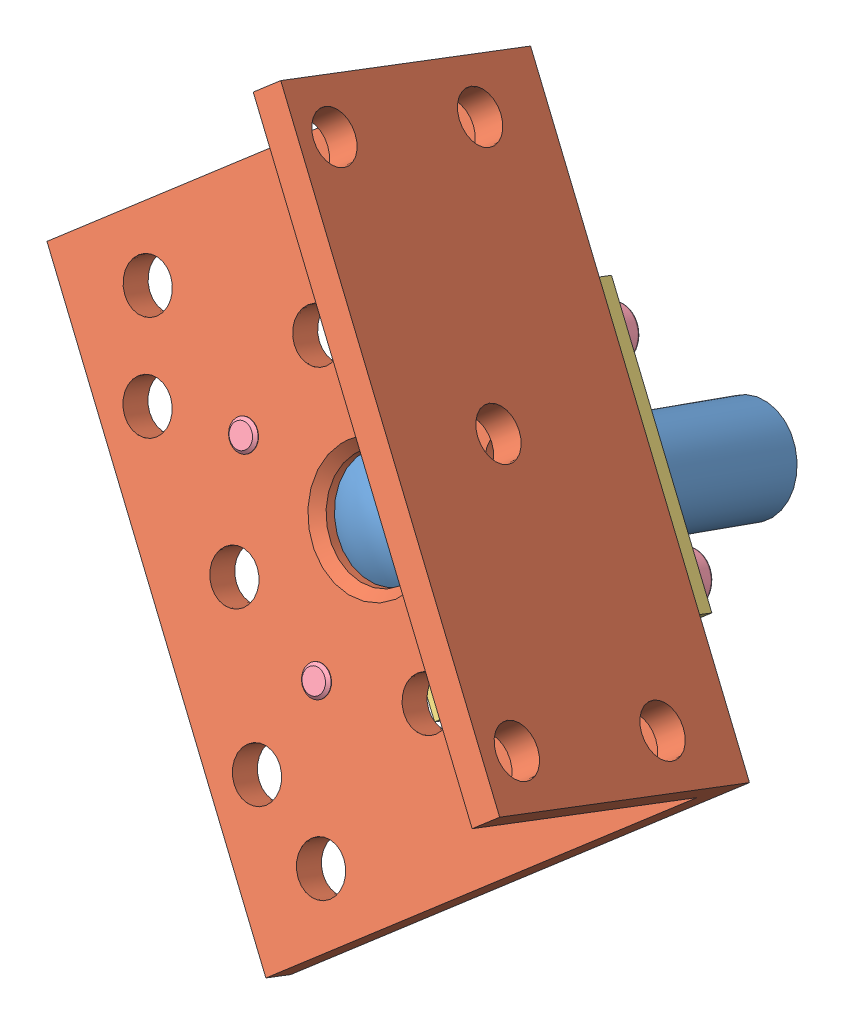
SolidWorks assembly Assemblage rotule v2, configuration Défaut. Lengths in mm.
Overall size (155.49 167.29 169.97).
7 component instances, 4 part files, 14 mates.
Components (placement in the parent):
- rotule v2-1: rotule v2 [Défaut] at (-163.3513 51.3692 -159.123) x (0.573473 -0.772184 0.273605) z (-0.81922 -0.539497 0.194477) size (38 87.57 38)
- support rotule v2-2: support rotule v2 [Défaut] at (-160.5548 83.4828 -76.8014) x (-0.661926 0.702138 -0.262403) z (-0.018758 -0.365479 -0.930631) size (120 100 60)
- plaque dessus rotule v2-2: plaque dessus rotule v2 [Défaut] at (-163.4271 69.4856 -107.0098) x (-0.661926 0.702138 -0.262403) z (-0.018758 -0.365479 -0.930631) size (55 55 6)
- m6x40-1: m6x40 [Défaut] at (-165.2878 41.0282 -102.2437) x (-0.14145 0.922402 -0.359396) z (-0.018758 -0.365479 -0.930631) size (10 10 46)
- m6x40-2: m6x40 [Défaut] at (-135.3145 65.4717 -112.4473) x (-0.230019 -0.90425 0.359755) z (-0.018758 -0.365479 -0.930631) size (10 10 46)
- m6x40-3: m6x40 [Défaut] at (-161.7915 93.5572 -122.9434) x (0.980648 -0.18815 0.054125) z (-0.018758 -0.365479 -0.930631) size (10 10 46)
- m6x40-4: m6x40 [Défaut] at (-191.7649 69.1137 -112.7398) x (0.7809 -0.586622 0.214639) z (-0.018758 -0.365479 -0.930631) size (10 10 46)
Mates (geometry in assembly coordinates):
- Parallèle4: parallel aligned: plane of support rotule v2-2 through (-237.8496 92.8639 -85.3748) normal (-0.749334 -0.611087 0.255091); plane of plaque dessus rotule v2-2 through (-202.3493 69.7966 -112.7946) normal (-0.749334 -0.611087 0.255091)
- Tangent1: tangent aligned: sphere of rotule v2-1; cone of support rotule v2-2 through (-162.8778 80.1877 -79.7586) axis (0.018758 0.365479 0.930631)
- Coaxiale4: concentric: sphere of rotule v2-1; cylinder of support rotule v2-2 through (-163.1029 75.8019 -90.9262) axis (0.018758 0.365479 0.930631) radius 11
- Parallèle5: parallel anti-aligned: plane of support rotule v2-2 through (-160.6674 81.29 -82.3852) normal (-0.018758 -0.365479 -0.930631); plane of plaque dessus rotule v2-2 through (-163.4271 69.4856 -107.0098) normal (0.018758 0.365479 0.930631)
- Coaxiale7: concentric: sphere of rotule v2-1; cylinder of plaque dessus rotule v2-2 through (-163.5397 67.2927 -112.5935) axis (0.018758 0.365479 0.930631) radius 11.5
- Coïncidente5: coincident anti-aligned: plane of plaque dessus rotule v2-2 through (-163.5397 67.2927 -112.5935) normal (-0.018758 -0.365479 -0.930631); plane of m6x40-1 through (-165.2878 41.0282 -102.2437) normal (0.018758 0.365479 0.930631)
- Coaxiale8: concentric anti-aligned: cylinder of plaque dessus rotule v2-2 through (-165.2878 41.0282 -102.2437) axis (0.018758 0.365479 0.930631) radius 3; cylinder of m6x40-1 through (-164.5375 55.6473 -65.0184) axis (-0.018758 -0.365479 -0.930631) radius 3
- Coïncidente6: coincident anti-aligned: plane of plaque dessus rotule v2-2 through (-163.5397 67.2927 -112.5935) normal (-0.018758 -0.365479 -0.930631); plane of m6x40-2 through (-135.3145 65.4717 -112.4473) normal (0.018758 0.365479 0.930631)
- Coaxiale9: concentric anti-aligned: cylinder of plaque dessus rotule v2-2 through (-135.3145 65.4717 -112.4473) axis (0.018758 0.365479 0.930631) radius 3; cylinder of m6x40-2 through (-134.5641 80.0908 -75.2221) axis (-0.018758 -0.365479 -0.930631) radius 3
- Coïncidente7: coincident anti-aligned: plane of plaque dessus rotule v2-2 through (-163.5397 67.2927 -112.5935) normal (-0.018758 -0.365479 -0.930631); plane of m6x40-3 through (-161.7915 93.5572 -122.9434) normal (0.018758 0.365479 0.930631)
- Coaxiale10: concentric anti-aligned: cylinder of plaque dessus rotule v2-2 through (-161.7915 93.5572 -122.9434) axis (0.018758 0.365479 0.930631) radius 3; cylinder of m6x40-3 through (-161.0412 108.1763 -85.7182) axis (-0.018758 -0.365479 -0.930631) radius 3
- Coïncidente8: coincident anti-aligned: plane of plaque dessus rotule v2-2 through (-163.5397 67.2927 -112.5935) normal (-0.018758 -0.365479 -0.930631); plane of m6x40-4 through (-191.7649 69.1137 -112.7398) normal (0.018758 0.365479 0.930631)
- Coaxiale11: concentric anti-aligned: cylinder of plaque dessus rotule v2-2 through (-191.7649 69.1137 -112.7398) axis (0.018758 0.365479 0.930631) radius 3; cylinder of m6x40-4 through (-191.0146 83.7329 -75.5146) axis (-0.018758 -0.365479 -0.930631) radius 3
- Distance2: distance = 27.2824 mm anti-aligned: plane of plaque dessus rotule v2-2 through (-163.4271 69.4856 -107.0098) normal (0.018758 0.365479 0.930631); plane of support rotule v2-2 through (-160.6674 81.29 -82.3852) normal (-0.018758 -0.365479 -0.930631)
